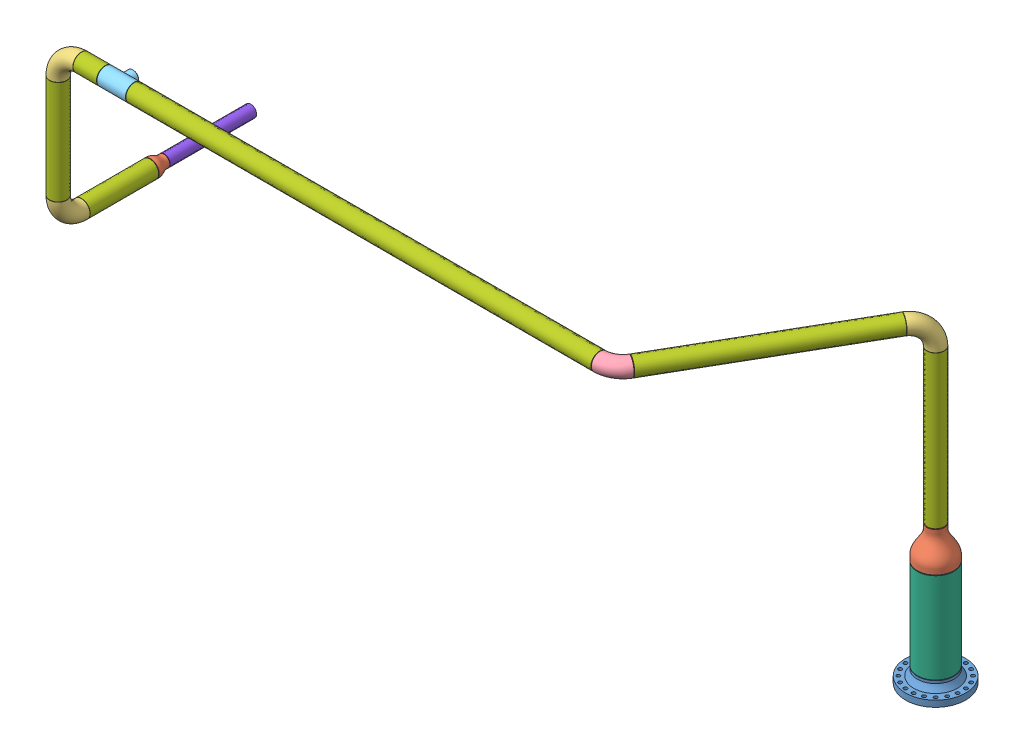
SolidWorks assembly Pipe2-SKLOP DISPOZICIJE, configuration Default. Lengths in mm.
Overall size (6966.5 3195.26 2402.86).
16 component instances, 8 part files, 2 mates.
Components (placement in the parent):
- welding neck flange-1: welding neck flange [WNeck Flange 400-NPS14] at (-11005.1015 1631 -11176) x (1 0 0) z (0 -1 0) size (584.2 584.2 165.71)
- reducer-1: reducer [REDUCER 14 x 6] at (-11005.1015 2659.952 -11176) x (0 1 0) z (1 0 0) size (350.2 355.63 355.63)
- reducer-3: reducer [REDUCER 6 x 4] at (-17560.6015 3237.15 -10078.9003) x (0 0 -1) z (1 0 0) size (159.7 168.28 168.28)
- 90deg LR Inch Elbow-1: 90deg LR Inch Elbow [90L LR Inch 6 Sch40] at (-11119.4015 4472.4 -10978.0266) x (0 -1 0) z (0.866025 0 0.5) size (322.76 322.76 168.35)
- 90deg LR Inch Elbow-3: 90deg LR Inch Elbow [90L LR Inch 6 Sch40] at (-17332.0015 4472.4 -9184.1416) size (322.76 322.76 168.35)
- 90deg LR Inch Elbow-4: 90deg LR Inch Elbow [90L LR Inch 6 Sch40] at (-17560.6015 3465.75 -9412.7416) x (0 1 0) z (1 0 0) size (322.76 322.76 168.35)
- 90deg LR Inch Elbow_Local1-Pipe2-SKLOP DISPOZICIJE-5: 90deg LR Inch Elbow_Local1-Pipe2-SKLOP DISPOZICIJE [D=6in, A=60deg, R=9in] at (-12287.0837 4701 -9412.7416) x (0 0 -1) z (0 -1 0) size (238.65 278.44 168.35)
- reducing outlet tee inch-1: reducing outlet tee inch [RTee Inch6x6x4Sch80] at (-16960.6015 4701 -9184.1416) x (-1 0 0) z (0 -1 0) size (305.5 224.19 168.28)
- 14inSchedule120-Pipe2-SKLOP DISPOZICIJE^Pipe2-SKLOP DISPOZICIJE-1: 14inSchedule120-Pipe2-SKLOP DISPOZICIJE^Pipe2-SKLOP DISPOZICIJE [14 in, Schedule 120] at (-11005.1015 1780.352 -11176) x (0.707107 0 0.707107) z (0 1 0) size (355.6 355.6 879.6) (virtual)
- 6inSchedule40-Pipe2-SKLOP DISPOZICIJE^Pipe2-SKLOP DISPOZICIJE-1: 6inSchedule40-Pipe2-SKLOP DISPOZICIJE^Pipe2-SKLOP DISPOZICIJE [6 in, Schedule 40] at (-11005.1015 2990.152 -11176) x (0.707107 0 0.707107) z (0 1 0) size (168.15 168.15 1482.25) (virtual)
- 6inSchedule40-Pipe2-SKLOP DISPOZICIJE^Pipe2-SKLOP DISPOZICIJE-2: 6inSchedule40-Pipe2-SKLOP DISPOZICIJE^Pipe2-SKLOP DISPOZICIJE [6 in, Schedule 40, 1] at (-11119.4015 4701 -10978.0266) x (0.654654 0.654654 0.377964) z (-0.5 0 0.866025) size (168.15 168.15 1939.42) (virtual)
- 6inSchedule40-Pipe2-SKLOP DISPOZICIJE^Pipe2-SKLOP DISPOZICIJE-3: 6inSchedule40-Pipe2-SKLOP DISPOZICIJE^Pipe2-SKLOP DISPOZICIJE [6 in, Schedule 40, 2] at (-12287.0837 4701 -9184.1416) x (0 0.707107 0.707107) z (-1 0 0) size (168.15 168.15 4530.77) (virtual)
- 6inSchedule40-Pipe2-SKLOP DISPOZICIJE^Pipe2-SKLOP DISPOZICIJE-4: 6inSchedule40-Pipe2-SKLOP DISPOZICIJE^Pipe2-SKLOP DISPOZICIJE [6 in, Schedule 40, 3] at (-17560.6015 4472.4 -9184.1416) x (0.707107 0 0.707107) z (0 -1 0) size (168.15 168.15 1006.65) (virtual)
- 6inSchedule40-Pipe2-SKLOP DISPOZICIJE^Pipe2-SKLOP DISPOZICIJE-5: 6inSchedule40-Pipe2-SKLOP DISPOZICIJE^Pipe2-SKLOP DISPOZICIJE [6 in, Schedule 40, 4] at (-17560.6015 3237.15 -9412.7416) x (0.707107 0.707107 0) z (0 0 -1) size (168.15 168.15 666.16) (virtual)
- 4inSchedule40-Pipe2-SKLOP DISPOZICIJE^Pipe2-SKLOP DISPOZICIJE-1: 4inSchedule40-Pipe2-SKLOP DISPOZICIJE^Pipe2-SKLOP DISPOZICIJE [4 in, Schedule 40] at (-17560.6015 3237.15 -10218.6003) x (0.707107 0.707107 0) z (0 0 -1) size (114.3 114.3 841.4) (virtual)
- 6inSchedule40-Pipe2-SKLOP DISPOZICIJE^Pipe2-SKLOP DISPOZICIJE-6: 6inSchedule40-Pipe2-SKLOP DISPOZICIJE^Pipe2-SKLOP DISPOZICIJE [6 in, Schedule 40, 7] at (-17103.3495 4701 -9184.1416) x (0 0.707107 0.707107) z (-1 0 0) size (168.15 168.15 228.65) (virtual)
Mates (geometry in assembly coordinates):
- Concentric141: concentric anti-aligned: cylinder of ? through (-11005.1015 1631 -11176) axis (0 -1 0) radius 212.725; cylinder of welding neck flange-1 through (-11005.1015 1624.65 -11176) axis (0 1 0) radius 212.725
- Coincident21261: coincident anti-aligned: plane of ? through (-11005.1015 1624.65 -11176) normal (0 1 0); plane of welding neck flange-1 through (-11005.1015 1624.65 -11176) normal (0 -1 0)
